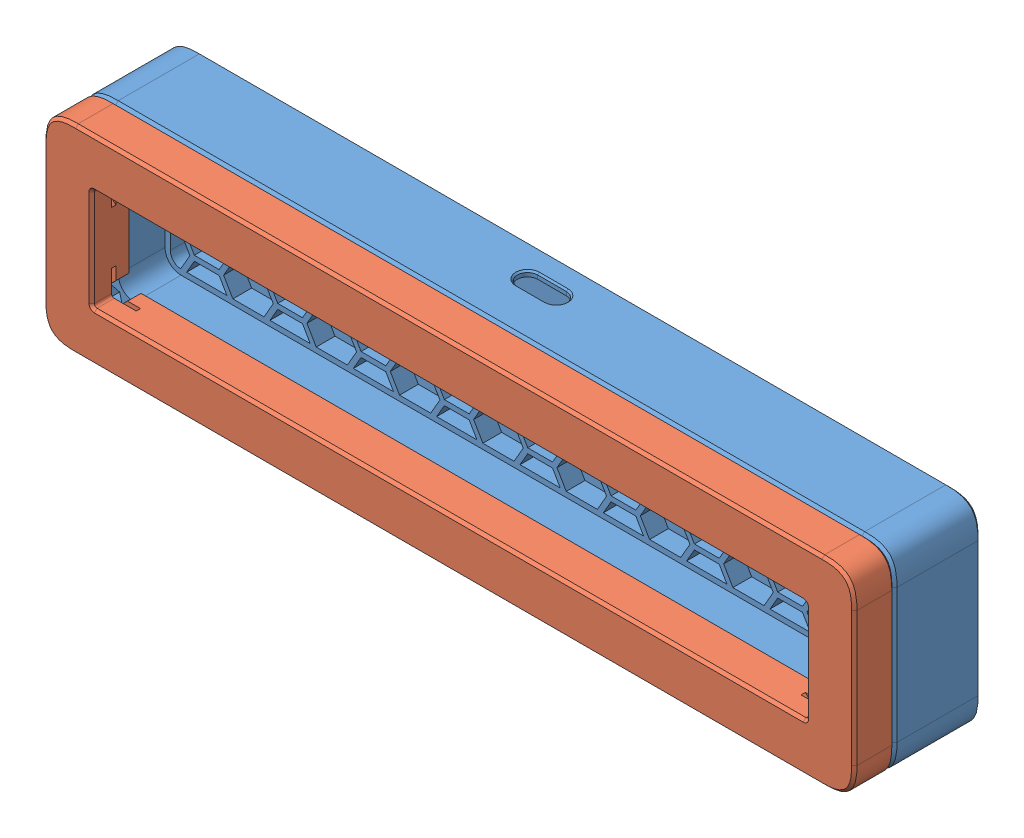
SolidWorks assembly case, configuration 默认. Lengths in mm.
Overall size (151.1 37.1 23.65).
2 component instances, 2 part files, 0 mates.
Components (placement in the parent):
- bottom-1: bottom [默认] at origin size (151.1 37.1 16.2)
- top-2: top [默认] at (0 0 16.051) size (151.1 37.1 8.55)
